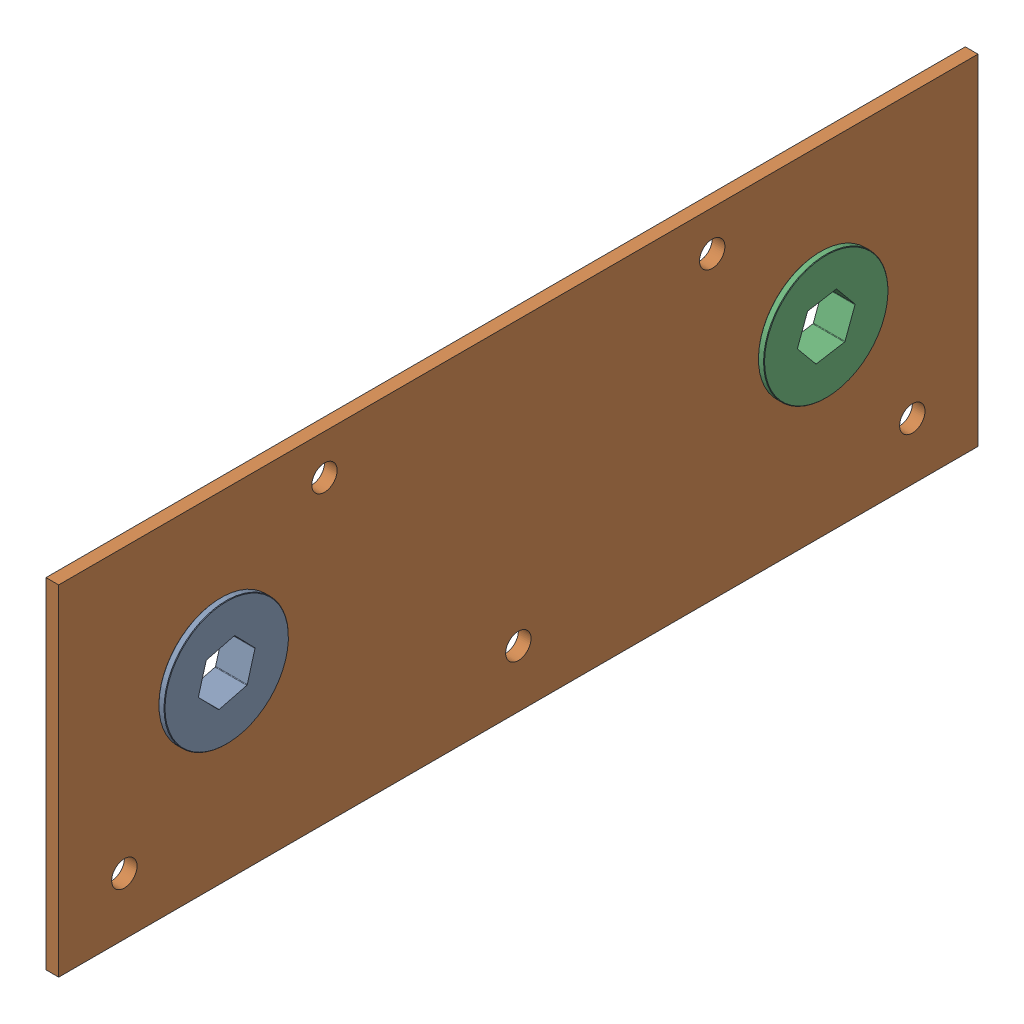
SolidWorks assembly Intake_Top_Bearing_Plate_Assembly, configuration Default. Lengths in mm.
Overall size (7.93 85 230).
3 component instances, 2 part files, 0 mates.
Components (placement in the parent):
- 1_2_Hex_Bore_Flange_Bearing-1: 1_2_Hex_Bore_Flange_Bearing [Default] at (80.5297 -24.7712 75) x (0 0.715549 0.698562) z (1 0 0) size (31.12 31.12 7.93)
- Intake_Top_Bottom_Bearing_Plate-1: Intake_Top_Bottom_Bearing_Plate [Default] at (83.25 -29.2712 0) size (3.17 85 230)
- 1_2_Hex_Bore_Flange_Bearing-2: 1_2_Hex_Bore_Flange_Bearing [Default] at (80.5297 -24.7712 -75) x (0 -0.16623 0.986087) z (1 0 0) size (31.12 31.12 7.93)
